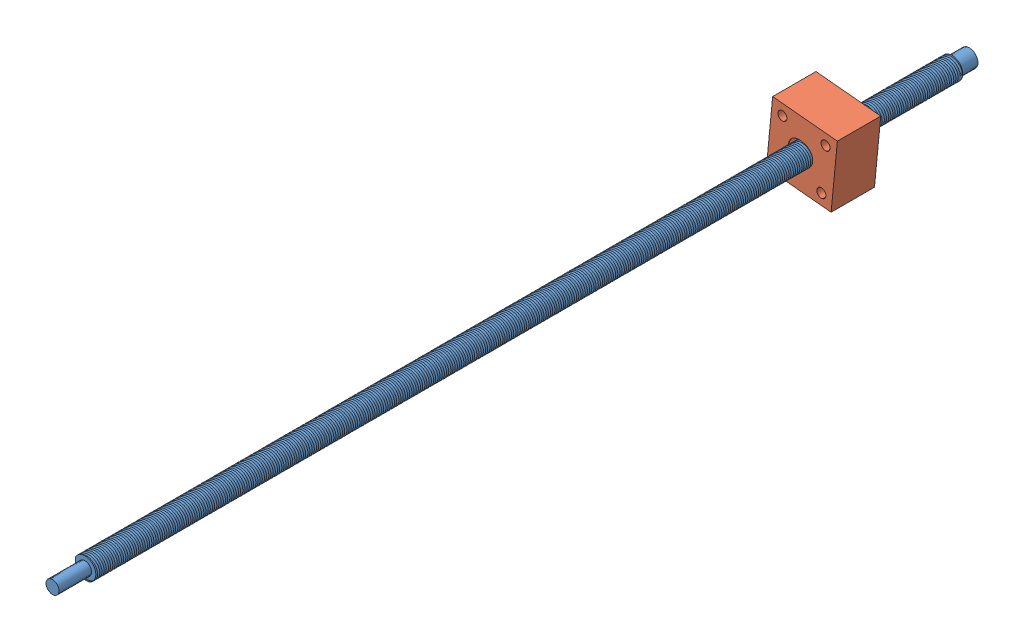
SolidWorks assembly TrapezoidalAssembly, configuration Default. Lengths in mm.
Overall size (69.78 416.52 423).
2 component instances, 2 part files, 3 mates.
Components (placement in the parent):
- Trapezoidal thread423mm-1: Trapezoidal thread423mm [Default] at (243.3481 272.0586 244.734) size (10 11.55 423)
- Trapezoidal Nut-1: Trapezoidal Nut [Default] at (243.3481 272.0586 293.9889) x (0.096036 0.995378 0) z (0 0 1) size (415.68 30 20.97)
Mates (geometry in assembly coordinates):
- Parallel1: parallel aligned: plane of Trapezoidal thread423mm-1 through (243.3481 272.0586 659.734) normal (0 0 1); plane of Trapezoidal Nut-1 through (243.3481 272.0586 313.9889) normal (0 0 1)
- Concentric1: concentric aligned: circle of Trapezoidal thread423mm-1; circle of Trapezoidal Nut-1
- Screw1: screw = 10 mm aligned: cylinder of Trapezoidal thread423mm-1 through (243.3481 272.0586 644.734) axis (0 0 -1) radius 5; cylinder of Trapezoidal Nut-1 through (243.3481 272.0586 313.9889) axis (0 0 -1) radius 5
